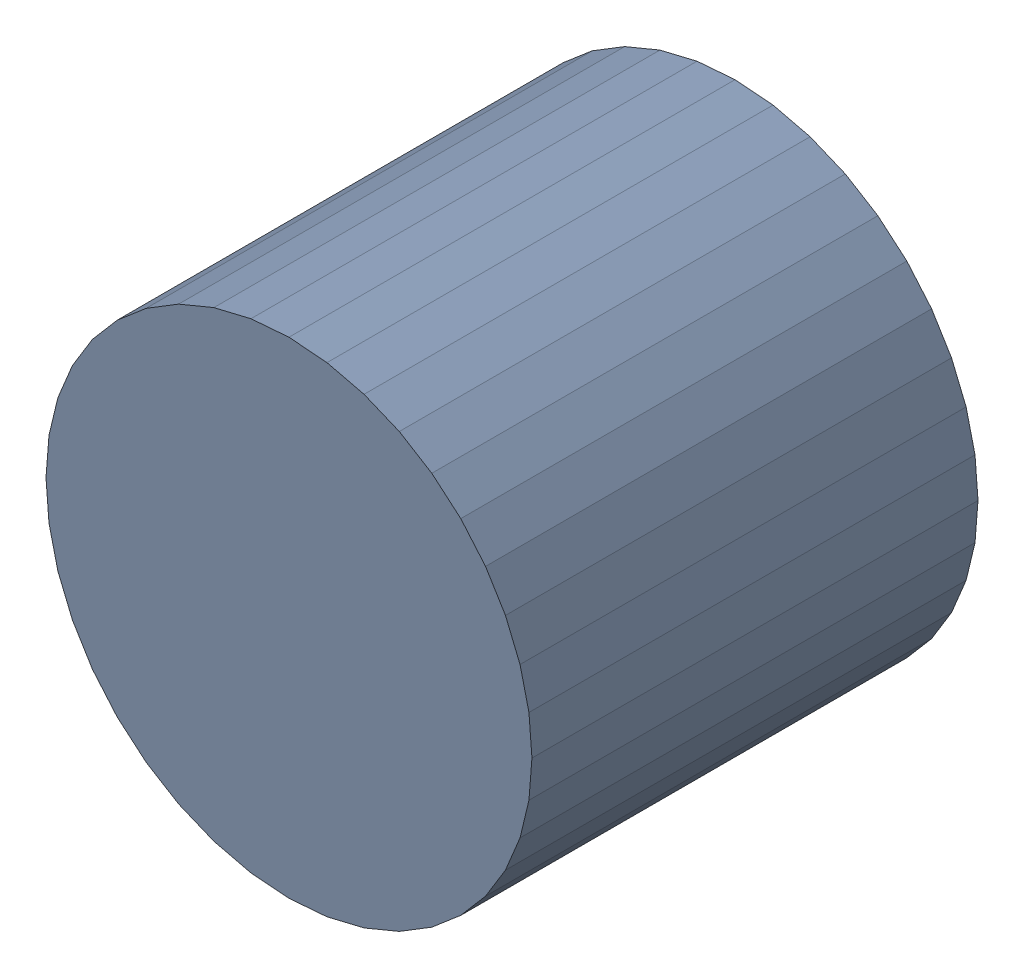
SolidWorks assembly USB01_C7, configuration Default. Lengths in mm.
Overall size (6.32 6.32 5.8).
2 component instances, 1 part files, 0 mates.
Components (placement in the parent):
- 384312384-1: 384312384 [Default] at (149.86 76.835 -6.9024) size (6.32 6.32 5.8)
  - Extruded_7-1: Extruded_7 [Default] at origin size (6.32 6.32 5.8)
